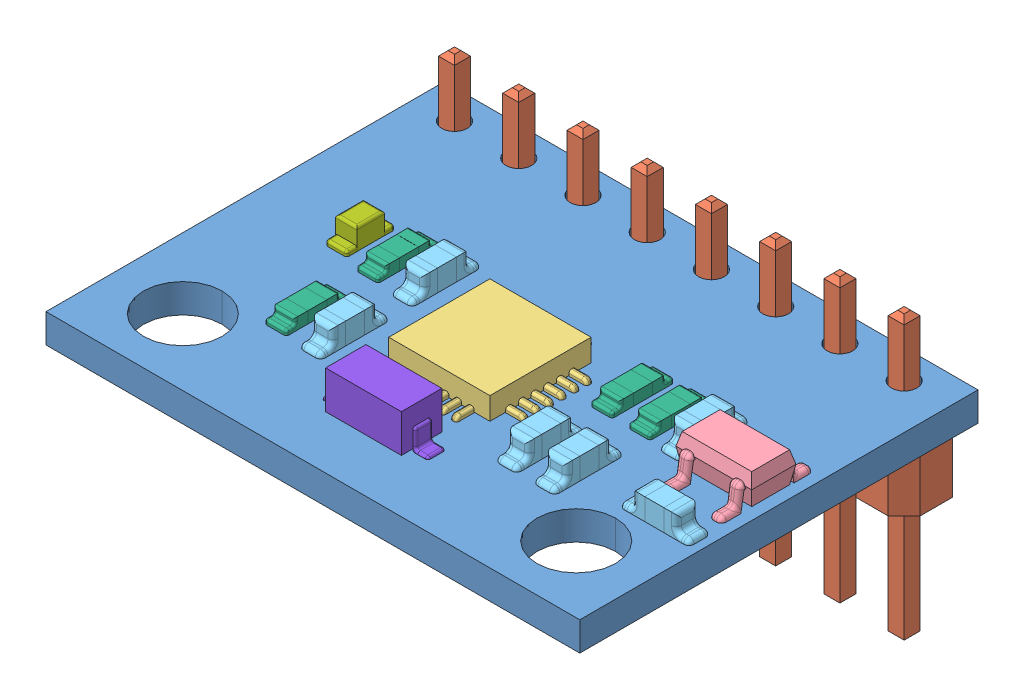
SolidWorks assembly MPU 6050 IMU, configuration Default. Lengths in mm.
Overall size (21.11 11.18 15.88).
24 component instances, 8 part files, 0 mates.
Components (placement in the parent):
- MPU 6050 IMU.STEP-1: MPU 6050 IMU.STEP [Default] at origin size (21.11 11.18 15.88)
  - Base.STEP-1: Base.STEP [Default] at (7.2489 10.9584 16.5726) size (21.11 1.14 15.75)
  - pin header.STEP-1: pin header.STEP [Default] at (16.0246 10.3869 9.8416) x (-1 0 0) z (0 0 1) size (2.54 11.18 2.54)
  - pin header.STEP-2: pin header.STEP [Default] at (13.4846 10.3869 9.8416) x (-1 0 0) z (0 0 1) size (2.54 11.18 2.54)
  - pin header.STEP-3: pin header.STEP [Default] at (10.9446 10.3869 9.8416) x (-1 0 0) z (0 0 1) size (2.54 11.18 2.54)
  - pin header.STEP-4: pin header.STEP [Default] at (8.4046 10.3869 9.8416) x (-1 0 0) z (0 0 1) size (2.54 11.18 2.54)
  - pin header.STEP-5: pin header.STEP [Default] at (5.8646 10.3869 9.8416) x (-1 0 0) z (0 0 1) size (2.54 11.18 2.54)
  - pin header.STEP-6: pin header.STEP [Default] at (3.3246 10.3869 9.8416) x (-1 0 0) z (0 0 1) size (2.54 11.18 2.54)
  - pin header.STEP-7: pin header.STEP [Default] at (0.7846 10.3869 9.8416) x (-1 0 0) z (0 0 1) size (2.54 11.18 2.54)
  - pin header.STEP-8: pin header.STEP [Default] at (-1.7554 10.3869 9.8416) x (-1 0 0) z (0 0 1) size (2.54 11.18 2.54)
  - sensor chip.STEP-1: sensor chip.STEP [Default] at (7.2489 11.5499 17.4466) size (5.4 0.9 5.4)
  - S2NH chip.STEP-1: S2NH chip.STEP [Default] at (16.1026 12.3799 16.5726) size (3 1.35 3.65)
  - Resistor small.STEP-1: Resistor small.STEP [Default] at (16.1026 11.5314 19.3726) size (2.75 0.94 0.95)
  - Resistor small.STEP-2: Resistor small.STEP [Default] at (13.9776 11.5314 15.6976) x (0 0 -1) z (1 0 0) size (2.75 0.94 0.95)
  - Resistor small black.STEP-1: Resistor small black.STEP [Default] at (12.6276 11.5299 15.6976) x (0 0 1) z (-1 0 0) size (2.45 0.54 0.95)
  - Resistor small black.STEP-2: Resistor small black.STEP [Default] at (11.1276 11.5299 15.6976) x (0 0 1) z (-1 0 0) size (2.45 0.54 0.95)
  - Resistor small.STEP-3: Resistor small.STEP [Default] at (12.6276 11.5314 19.3216) x (0 0 -1) z (1 0 0) size (2.75 0.94 0.95)
  - Resistor small.STEP-4: Resistor small.STEP [Default] at (11.1276 11.5314 19.3216) x (0 0 -1) z (1 0 0) size (2.75 0.94 0.95)
  - Resistor small.STEP-5: Resistor small.STEP [Default] at (3.3702 11.5314 19.3216) x (0 0 -1) z (1 0 0) size (2.75 0.94 0.95)
  - Resistor small black.STEP-3: Resistor small black.STEP [Default] at (1.8702 11.5299 15.6968) x (0 0 -1) z (1 0 0) size (2.45 0.54 0.95)
  - Resistor small.STEP-6: Resistor small.STEP [Default] at (3.3702 11.5314 15.6976) x (0 0 1) z (-1 0 0) size (2.75 0.94 0.95)
  - Small LED.STEP-1: Small LED.STEP [Default] at (0.3652 11.5299 15.6976) size (0.85 0.84 1.9)
  - Resistor small black.STEP-4: Resistor small black.STEP [Default] at (1.8702 11.5299 19.3216) x (0 0 1) z (-1 0 0) size (2.45 0.54 0.95)
  - Resistor black.STEP-1: Resistor black.STEP [Default] at (7.2489 12.3799 21.6466) size (4.2 1.6 1.6)
